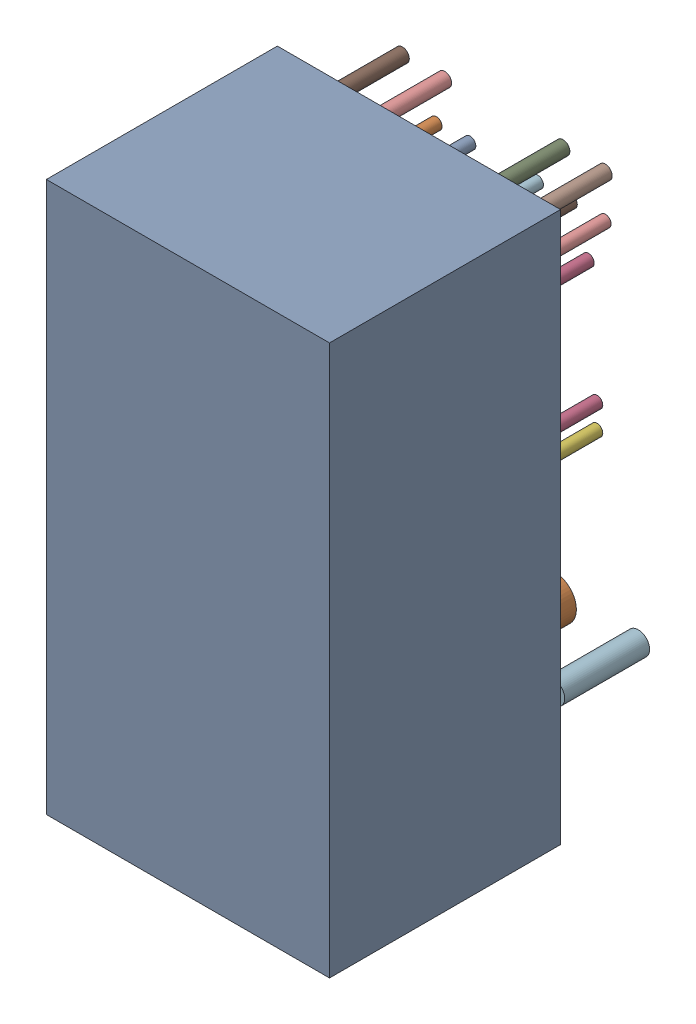
SolidWorks assembly 6024909664.step, configuration Default. Lengths in mm.
Overall size (17.5 33.02 18.97).
3 component instances, 3 part files, 0 mates.
Components (placement in the parent):
- Body.step-1: Body.step [Default] at (0 0 0.1) size (17 33.02 13.87)
- Lugs.step-1: Lugs.step [Default] at origin size (15.3 2.6 1.8)
- Leads.step-1: Leads.step [Default] at origin size (17.5 24.59 5.1)
